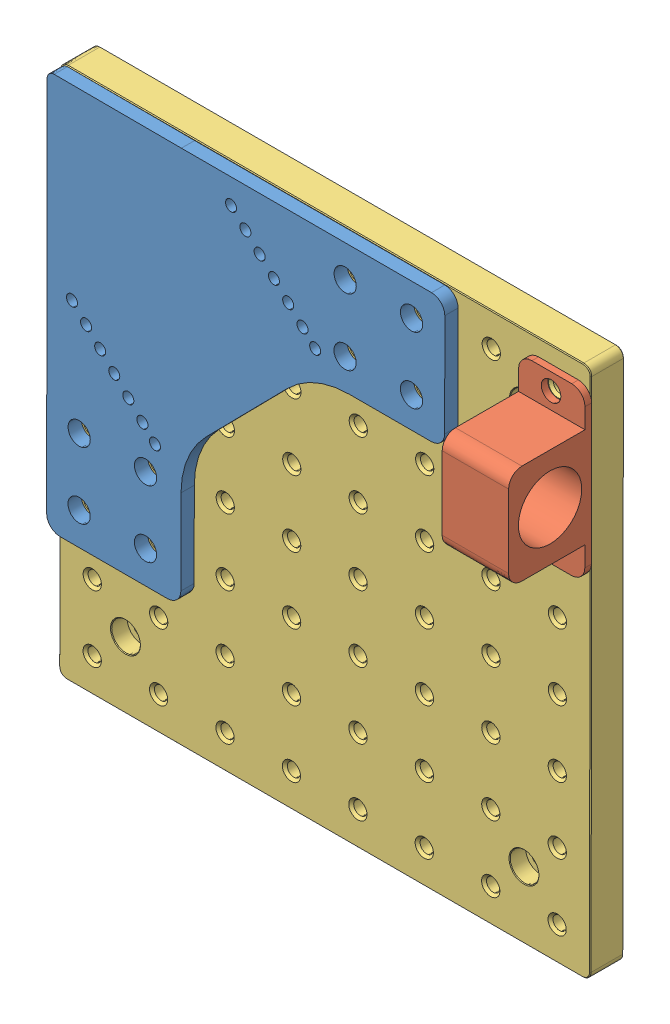
SolidWorks assembly ldass, configuration Default. Lengths in mm.
Overall size (203.48 203.22 44.54).
3 component instances, 3 part files, 0 mates.
Components (placement in the parent):
- Part 1-1: Part 1 [Default] at (-11.2978 96.6361 -29.458) x (1 0 0) z (0 0.001223 0.999999) size (152.1 151.8 5.08)
- Part 1_1-1: Part 1_1 [Default] at (72.7954 98.3429 -13.585) x (0 0.999999 -0.001223) z (0 0.001223 0.999999) size (63.5 25.4 31.75)
- Part 1_3-1: Part 1_3 [Default] at (-3.681 34.7951 -42.0823) x (1 0 0) z (0 -0.999999 0.001223) size (203.2 12.7 203.21)
